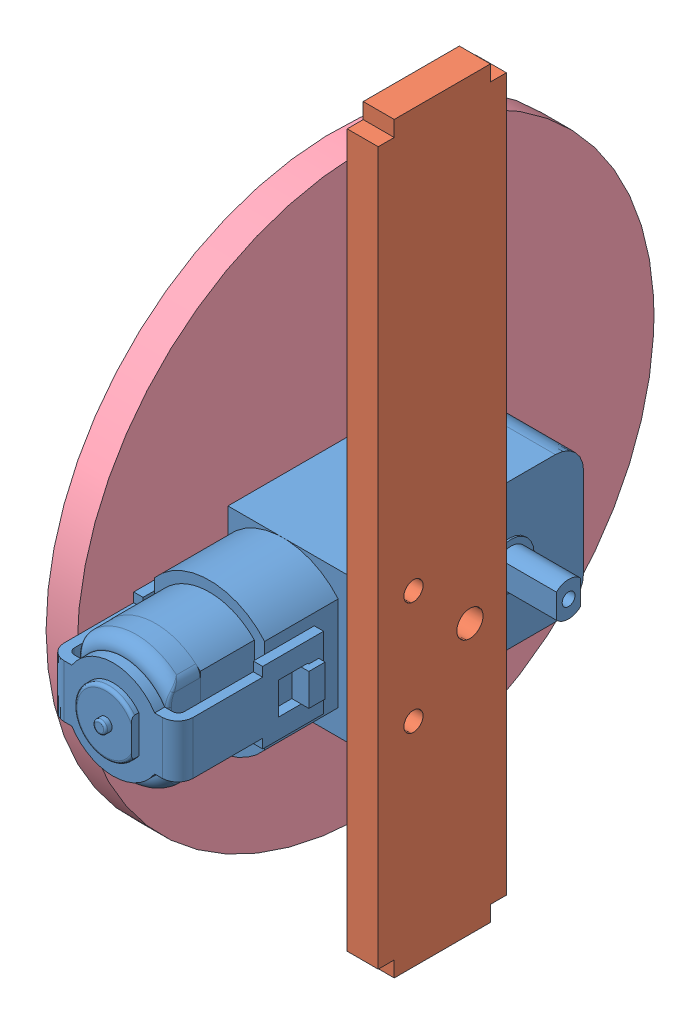
SolidWorks assembly Llanta - Derecha, configuration Predeterminado. Lengths in mm.
Overall size (37.12 119 98.96).
4 component instances, 4 part files, 6 mates.
Components (placement in the parent):
- Motor - Amarillo DC 3-6 V-1: Motor - Amarillo DC 3-6 V [Predeterminado] at (-6.191 1.1029 58.84) size (37.12 22.62 70.64)
- Acrilico - Motor Columna-1: Acrilico - Motor Columna [Predeterminado] at (3.809 1.1029 67.28) size (4.84 116 20)
- Acrilico - Llanta Acople-1: Acrilico - Llanta Acople [Predeterminado] at (-18.611 1.1029 52) size (2.44 10 10)
- Acrilico - Llanta-1: Acrilico - Llanta [Predeterminado] at (-23.451 1.1029 52) size (4.84 90 90)
Mates (geometry in assembly coordinates):
- Concéntrica1: concentric anti-aligned: circle of Motor - Amarillo DC 3-6 V-1; circle of Acrilico - Llanta Acople-1
- Coincidente3: coincident anti-aligned: plane of Motor - Amarillo DC 3-6 V-1 through (-16.171 1.1029 52) normal (-1 0 0); plane of Acrilico - Llanta Acople-1 through (-16.171 1.1029 52) normal (1 0 0)
- Concéntrica2: concentric anti-aligned: circle of Motor - Amarillo DC 3-6 V-1; circle of Acrilico - Llanta-1
- Coincidente9: coincident anti-aligned: plane of Acrilico - Llanta Acople-1 through (-18.611 1.1029 52) normal (-1 0 0); plane of Acrilico - Llanta-1 through (-18.611 1.1029 52) normal (1 0 0)
- Concéntrica3: concentric aligned: circle of Motor - Amarillo DC 3-6 V-1; circle of Acrilico - Motor Columna-1
- Coincidente11: coincident aligned: circle of Motor - Amarillo DC 3-6 V-1; circle of Acrilico - Motor Columna-1
